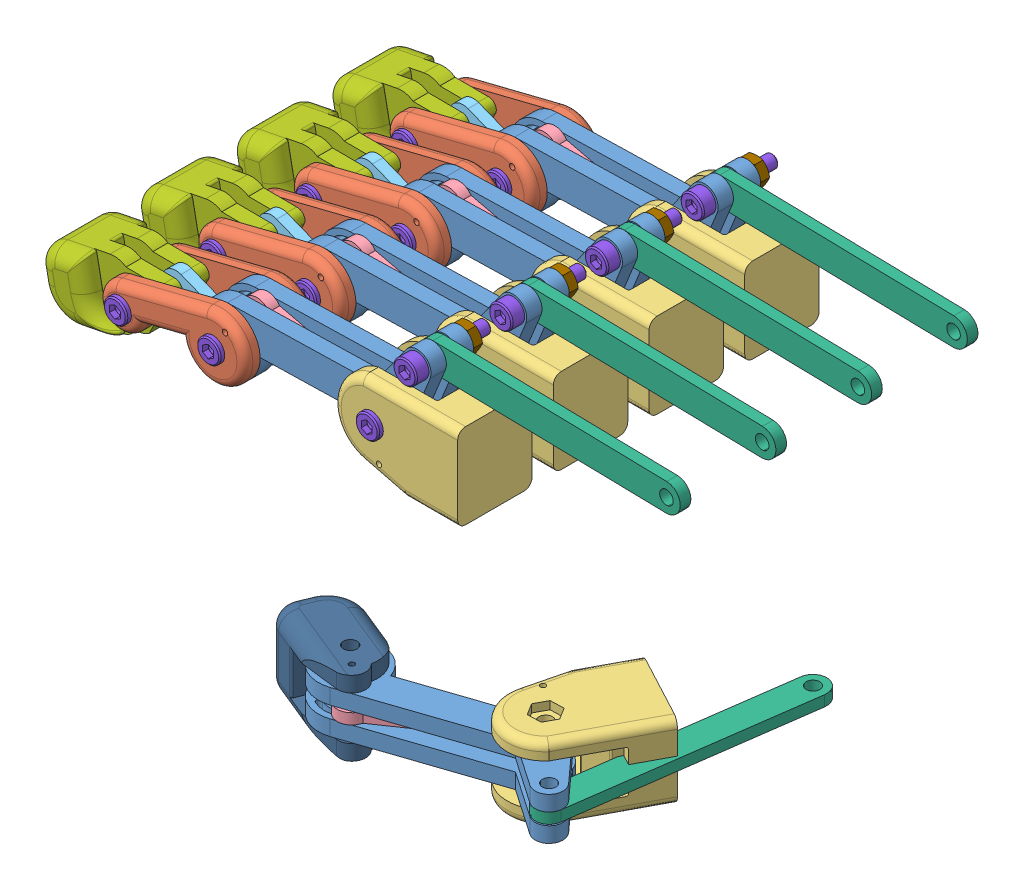
SolidWorks assembly Assem3, configuration Default. Lengths in mm.
Overall size (188.69 46.58 162.14).
79 component instances, 10 part files, 16 mates.
Components (placement in the parent):
- NotMyFinger-1: NotMyFinger [Default] at (20.0806 112.9124 103.3991) size (144.78 35.18 20.88) (flexible)
  - Joint1A-1: Joint1A [Default] at (46.4108 -14.225 49.7475) x (0.024106 -0.999709 0) z (0 0 -1) size (26.75 55.59 3.6)
  - Joint2A-1: Joint2A [HoleA] at (8.9819 -17.6283 53.3475) x (0.242286 -0.970205 0) z (0 0 -1) size (15 34.5 3.64)
  - Joint1A-2: Joint1A [Default] at (46.4108 -14.225 43.3475) x (0.024106 -0.999709 0) z (0 0 -1) size (26.75 55.59 3.6)
  - Joint2A-2: Joint2A [Default] at (8.9819 -17.6283 39.7475) x (0.242286 -0.970205 0) z (0 0 -1) size (15 34.5 3.64)
  - base-1: base [Default] at (66.6608 -5.475 35.9975) x (0 0 1) z (0 -1 0) size (17.57 29.25 20)
  - Link1A-1: Link1A [Default] at (48.1608 -21.475 43.3475) x (0.229287 0.973359 0) z (0.973359 -0.229287 0) size (10 2.5 45.77)
  - Link2A-1: Link2A [Default] at (9.1145 -23.1267 43.4475) x (0.370051 0.929011 0) z (0 0 1) size (6.5 24 2.5)
  - Link3A-1: Link3A [Default] at (108.4059 -1.7409 43.6475) x (0.999766 -0.021615 0) z (0 0 1) size (61.5 6.5 2.5)
  - FingerTip-1: FingerTip [Default] at (-12.9683 -20.5331 44.8225) x (-0.193934 0.981015 0) z (0 0 1) size (15.06 27.26 18.86)
  - socket head cap screw_am-1: socket head cap screw_am [B18.3.1M - 3 x 0.5 x 16 Hex SHCS -- 16NHX] at (-12.9683 -20.5331 54.4725) x (0 0 -1) z (1 0 0) size (19 5.5 5.5)
  - socket head cap screw_am-2: socket head cap screw_am [B18.3.1M - 3 x 0.5 x 16 Hex SHCS -- 16NHX] at (8.9819 -17.6283 54.4725) x (0 0 -1) z (1 0 0) size (19 5.5 5.5)
  - socket head cap screw_am-3: socket head cap screw_am [B18.3.1M - 3 x 0.5 x 16 Hex SHCS -- 16NHX] at (46.4108 -14.225 54.6225) x (0 0 -1) z (1 0 0) size (19 5.5 5.5)
  - hex nut style 1_am-1: hex nut style 1_am [B18.2.4.1M - Hex nut, Style 1,  M3 x 0.5 --D-N] at (46.4108 -14.225 35.4725) x (0.866025 0.5 0) z (0 0 -1) size (5.5 6.35 2.4)
  - hex nut style 1_am-2: hex nut style 1_am [B18.2.4.1M - Hex nut, Style 1,  M3 x 0.5 --D-N] at (8.9819 -17.6283 35.6225) x (0.719079 0.694929 0) z (0 0 -1) size (5.5 6.35 2.4)
  - hex nut style 1_am-3: hex nut style 1_am [B18.2.4.1M - Hex nut, Style 1,  M3 x 0.5 --D-N] at (-12.9683 -20.5331 35.6225) x (0.719079 0.694929 0) z (0 0 -1) size (5.5 6.35 2.4)
  - socket head cap screw_am-4: socket head cap screw_am [B18.3.1M - 3 x 0.5 x 16 Hex SHCS -- 16NHX] at (53.4188 -0.5521 52.7475) x (0 0 -1) z (1 0 0) size (19 5.5 5.5)
  - hex nut style 1_am-4: hex nut style 1_am [B18.2.4.1M - Hex nut, Style 1,  M3 x 0.5 --D-N] at (53.4188 -0.5521 37.3475) x (0.866025 0.5 0) z (0 0 -1) size (5.5 6.35 2.4)
- NotMyFinger-2: NotMyFinger [Default] at (20.0806 112.9124 80.8991) size (144.78 35.18 20.88) (flexible)
  - Joint1A-1: Joint1A [Default] at (46.4108 -14.225 49.7475) x (0.024106 -0.999709 0) z (0 0 -1) size (26.75 55.59 3.6)
  - Joint2A-1: Joint2A [HoleA] at (8.9819 -17.6283 53.3475) x (0.242286 -0.970205 0) z (0 0 -1) size (15 34.5 3.64)
  - Joint1A-2: Joint1A [Default] at (46.4108 -14.225 43.3475) x (0.024106 -0.999709 0) z (0 0 -1) size (26.75 55.59 3.6)
  - Joint2A-2: Joint2A [Default] at (8.9819 -17.6283 39.7475) x (0.242286 -0.970205 0) z (0 0 -1) size (15 34.5 3.64)
  - base-1: base [Default] at (66.6608 -5.475 35.9975) x (0 0 1) z (0 -1 0) size (17.57 29.25 20)
  - Link1A-1: Link1A [Default] at (48.1608 -21.475 43.3475) x (0.229287 0.973359 0) z (0.973359 -0.229287 0) size (10 2.5 45.77)
  - Link2A-1: Link2A [Default] at (9.1145 -23.1267 43.4475) x (0.370051 0.929011 0) z (0 0 1) size (6.5 24 2.5)
  - Link3A-1: Link3A [Default] at (108.4059 -1.7409 43.6475) x (0.999766 -0.021615 0) z (0 0 1) size (61.5 6.5 2.5)
  - FingerTip-1: FingerTip [Default] at (-12.9683 -20.5331 44.8225) x (-0.193934 0.981015 0) z (0 0 1) size (15.06 27.26 18.86)
  - socket head cap screw_am-1: socket head cap screw_am [B18.3.1M - 3 x 0.5 x 16 Hex SHCS -- 16NHX] at (-12.9683 -20.5331 54.4725) x (0 0 -1) z (1 0 0) size (19 5.5 5.5)
  - socket head cap screw_am-2: socket head cap screw_am [B18.3.1M - 3 x 0.5 x 16 Hex SHCS -- 16NHX] at (8.9819 -17.6283 54.4725) x (0 0 -1) z (1 0 0) size (19 5.5 5.5)
  - socket head cap screw_am-3: socket head cap screw_am [B18.3.1M - 3 x 0.5 x 16 Hex SHCS -- 16NHX] at (46.4108 -14.225 54.6225) x (0 0 -1) z (1 0 0) size (19 5.5 5.5)
  - hex nut style 1_am-1: hex nut style 1_am [B18.2.4.1M - Hex nut, Style 1,  M3 x 0.5 --D-N] at (46.4108 -14.225 35.4725) x (0.866025 0.5 0) z (0 0 -1) size (5.5 6.35 2.4)
  - hex nut style 1_am-2: hex nut style 1_am [B18.2.4.1M - Hex nut, Style 1,  M3 x 0.5 --D-N] at (8.9819 -17.6283 35.6225) x (0.719079 0.694929 0) z (0 0 -1) size (5.5 6.35 2.4)
  - hex nut style 1_am-3: hex nut style 1_am [B18.2.4.1M - Hex nut, Style 1,  M3 x 0.5 --D-N] at (-12.9683 -20.5331 35.6225) x (0.719079 0.694929 0) z (0 0 -1) size (5.5 6.35 2.4)
  - socket head cap screw_am-4: socket head cap screw_am [B18.3.1M - 3 x 0.5 x 16 Hex SHCS -- 16NHX] at (53.4188 -0.5521 52.7475) x (0 0 -1) z (1 0 0) size (19 5.5 5.5)
  - hex nut style 1_am-4: hex nut style 1_am [B18.2.4.1M - Hex nut, Style 1,  M3 x 0.5 --D-N] at (53.4188 -0.5521 37.3475) x (0.866025 0.5 0) z (0 0 -1) size (5.5 6.35 2.4)
- NotMyFinger-3: NotMyFinger [Default] at (20.0806 112.9124 58.3991) size (144.78 35.18 20.88) (flexible)
  - Joint1A-1: Joint1A [Default] at (46.4108 -14.225 49.7475) x (0.024106 -0.999709 0) z (0 0 -1) size (26.75 55.59 3.6)
  - Joint2A-1: Joint2A [HoleA] at (8.9819 -17.6283 53.3475) x (0.242286 -0.970205 0) z (0 0 -1) size (15 34.5 3.64)
  - Joint1A-2: Joint1A [Default] at (46.4108 -14.225 43.3475) x (0.024106 -0.999709 0) z (0 0 -1) size (26.75 55.59 3.6)
  - Joint2A-2: Joint2A [Default] at (8.9819 -17.6283 39.7475) x (0.242286 -0.970205 0) z (0 0 -1) size (15 34.5 3.64)
  - base-1: base [Default] at (66.6608 -5.475 35.9975) x (0 0 1) z (0 -1 0) size (17.57 29.25 20)
  - Link1A-1: Link1A [Default] at (48.1608 -21.475 43.3475) x (0.229287 0.973359 0) z (0.973359 -0.229287 0) size (10 2.5 45.77)
  - Link2A-1: Link2A [Default] at (9.1145 -23.1267 43.4475) x (0.370051 0.929011 0) z (0 0 1) size (6.5 24 2.5)
  - Link3A-1: Link3A [Default] at (108.4059 -1.7409 43.6475) x (0.999766 -0.021615 0) z (0 0 1) size (61.5 6.5 2.5)
  - FingerTip-1: FingerTip [Default] at (-12.9683 -20.5331 44.8225) x (-0.193934 0.981015 0) z (0 0 1) size (15.06 27.26 18.86)
  - socket head cap screw_am-1: socket head cap screw_am [B18.3.1M - 3 x 0.5 x 16 Hex SHCS -- 16NHX] at (-12.9683 -20.5331 54.4725) x (0 0 -1) z (1 0 0) size (19 5.5 5.5)
  - socket head cap screw_am-2: socket head cap screw_am [B18.3.1M - 3 x 0.5 x 16 Hex SHCS -- 16NHX] at (8.9819 -17.6283 54.4725) x (0 0 -1) z (1 0 0) size (19 5.5 5.5)
  - socket head cap screw_am-3: socket head cap screw_am [B18.3.1M - 3 x 0.5 x 16 Hex SHCS -- 16NHX] at (46.4108 -14.225 54.6225) x (0 0 -1) z (1 0 0) size (19 5.5 5.5)
  - hex nut style 1_am-1: hex nut style 1_am [B18.2.4.1M - Hex nut, Style 1,  M3 x 0.5 --D-N] at (46.4108 -14.225 35.4725) x (0.866025 0.5 0) z (0 0 -1) size (5.5 6.35 2.4)
  - hex nut style 1_am-2: hex nut style 1_am [B18.2.4.1M - Hex nut, Style 1,  M3 x 0.5 --D-N] at (8.9819 -17.6283 35.6225) x (0.719079 0.694929 0) z (0 0 -1) size (5.5 6.35 2.4)
  - hex nut style 1_am-3: hex nut style 1_am [B18.2.4.1M - Hex nut, Style 1,  M3 x 0.5 --D-N] at (-12.9683 -20.5331 35.6225) x (0.719079 0.694929 0) z (0 0 -1) size (5.5 6.35 2.4)
  - socket head cap screw_am-4: socket head cap screw_am [B18.3.1M - 3 x 0.5 x 16 Hex SHCS -- 16NHX] at (53.4188 -0.5521 52.7475) x (0 0 -1) z (1 0 0) size (19 5.5 5.5)
  - hex nut style 1_am-4: hex nut style 1_am [B18.2.4.1M - Hex nut, Style 1,  M3 x 0.5 --D-N] at (53.4188 -0.5521 37.3475) x (0.866025 0.5 0) z (0 0 -1) size (5.5 6.35 2.4)
- NotMyFinger-4: NotMyFinger [Default] at (20.0806 112.9124 35.8991) size (144.78 35.18 20.88) (flexible)
  - Joint1A-1: Joint1A [Default] at (46.4108 -14.225 49.7475) x (0.024106 -0.999709 0) z (0 0 -1) size (26.75 55.59 3.6)
  - Joint2A-1: Joint2A [HoleA] at (8.9819 -17.6283 53.3475) x (0.242286 -0.970205 0) z (0 0 -1) size (15 34.5 3.64)
  - Joint1A-2: Joint1A [Default] at (46.4108 -14.225 43.3475) x (0.024106 -0.999709 0) z (0 0 -1) size (26.75 55.59 3.6)
  - Joint2A-2: Joint2A [Default] at (8.9819 -17.6283 39.7475) x (0.242286 -0.970205 0) z (0 0 -1) size (15 34.5 3.64)
  - base-1: base [Default] at (66.6608 -5.475 35.9975) x (0 0 1) z (0 -1 0) size (17.57 29.25 20)
  - Link1A-1: Link1A [Default] at (48.1608 -21.475 43.3475) x (0.229287 0.973359 0) z (0.973359 -0.229287 0) size (10 2.5 45.77)
  - Link2A-1: Link2A [Default] at (9.1145 -23.1267 43.4475) x (0.370051 0.929011 0) z (0 0 1) size (6.5 24 2.5)
  - Link3A-1: Link3A [Default] at (108.4059 -1.7409 43.6475) x (0.999766 -0.021615 0) z (0 0 1) size (61.5 6.5 2.5)
  - FingerTip-1: FingerTip [Default] at (-12.9683 -20.5331 44.8225) x (-0.193934 0.981015 0) z (0 0 1) size (15.06 27.26 18.86)
  - socket head cap screw_am-1: socket head cap screw_am [B18.3.1M - 3 x 0.5 x 16 Hex SHCS -- 16NHX] at (-12.9683 -20.5331 54.4725) x (0 0 -1) z (1 0 0) size (19 5.5 5.5)
  - socket head cap screw_am-2: socket head cap screw_am [B18.3.1M - 3 x 0.5 x 16 Hex SHCS -- 16NHX] at (8.9819 -17.6283 54.4725) x (0 0 -1) z (1 0 0) size (19 5.5 5.5)
  - socket head cap screw_am-3: socket head cap screw_am [B18.3.1M - 3 x 0.5 x 16 Hex SHCS -- 16NHX] at (46.4108 -14.225 54.6225) x (0 0 -1) z (1 0 0) size (19 5.5 5.5)
  - hex nut style 1_am-1: hex nut style 1_am [B18.2.4.1M - Hex nut, Style 1,  M3 x 0.5 --D-N] at (46.4108 -14.225 35.4725) x (0.866025 0.5 0) z (0 0 -1) size (5.5 6.35 2.4)
  - hex nut style 1_am-2: hex nut style 1_am [B18.2.4.1M - Hex nut, Style 1,  M3 x 0.5 --D-N] at (8.9819 -17.6283 35.6225) x (0.719079 0.694929 0) z (0 0 -1) size (5.5 6.35 2.4)
  - hex nut style 1_am-3: hex nut style 1_am [B18.2.4.1M - Hex nut, Style 1,  M3 x 0.5 --D-N] at (-12.9683 -20.5331 35.6225) x (0.719079 0.694929 0) z (0 0 -1) size (5.5 6.35 2.4)
  - socket head cap screw_am-4: socket head cap screw_am [B18.3.1M - 3 x 0.5 x 16 Hex SHCS -- 16NHX] at (53.4188 -0.5521 52.7475) x (0 0 -1) z (1 0 0) size (19 5.5 5.5)
  - hex nut style 1_am-4: hex nut style 1_am [B18.2.4.1M - Hex nut, Style 1,  M3 x 0.5 --D-N] at (53.4188 -0.5521 37.3475) x (0.866025 0.5 0) z (0 0 -1) size (5.5 6.35 2.4)
- Thumb-1: Thumb [Default] at (185.4496 84.8281 177.4523) x (0 -1 0) z (-0.882383 0 -0.470531) size (17.69 96.11 65.16) (flexible)
  - base-1: base [Default] at (-2.6093 9.3209 33.628) size (17.57 29.25 20)
  - Joint1A-1: Joint1A [Default] at (4.7407 29.5709 42.378) x (0 -0.685985 0.727616) z (-1 0 0) size (26.75 55.59 3.6)
  - Joint1A-2: Joint1A [Default] at (11.1407 29.5709 42.378) x (0 -0.685985 0.727616) z (-1 0 0) size (26.75 55.59 3.6)
  - Link1A-1: Link1A [shorter] at (4.7407 27.8209 49.628) x (0 0.462623 -0.886555) z (0 -0.886555 -0.462623) size (10 2.5 40.77)
  - Link3A-1: Link3A [Default] at (4.7407 33.4942 27.5231) x (0 0.93868 -0.344789) z (1 0 0) size (61.5 6.5 2.5)
  - ThumbTip-1: ThumbTip [Default] at (5.9907 55.1415 69.9215) x (0 0.994953 -0.100344) z (1 0 0) size (15.03 25.92 17.5)
Mates (geometry in assembly coordinates):
- Coincident1: coincident aligned: plane of NotMyFinger-1/base-1 through (86.7413 87.4374 156.8966) normal (1 0 0); plane of NotMyFinger-2/base-1 through (86.7413 87.4374 134.3966) normal (1 0 0)
- Coincident2: coincident aligned: plane of NotMyFinger-2/base-1 through (86.7413 87.4374 134.3966) normal (1 0 0); plane of NotMyFinger-3/base-1 through (86.7413 87.4374 111.8966) normal (1 0 0)
- Coincident3: coincident aligned: plane of NotMyFinger-3/base-1 through (86.7413 87.4374 111.8966) normal (1 0 0); plane of NotMyFinger-4/base-1 through (86.7413 87.4374 89.3966) normal (1 0 0)
- Coincident4: coincident aligned: plane of NotMyFinger-1/base-1 through (86.7413 107.4374 139.3966) normal (0 1 0); plane of NotMyFinger-2/base-1 through (86.7413 107.4374 116.8966) normal (0 1 0)
- Coincident5: coincident aligned: plane of NotMyFinger-2/base-1 through (86.7413 107.4374 116.8966) normal (0 1 0); plane of NotMyFinger-3/base-1 through (86.7413 107.4374 94.3966) normal (0 1 0)
- Coincident6: coincident aligned: plane of NotMyFinger-3/base-1 through (86.7413 107.4374 94.3966) normal (0 1 0); plane of NotMyFinger-4/base-1 through (86.7413 107.4374 71.8966) normal (0 1 0)
- Coincident7: coincident anti-aligned: plane of NotMyFinger-1/base-1 through (86.7413 87.4374 139.3966) normal (0 -1 0); plane of Thumb-1/base-1 through (133.7433 87.4374 160.4432) normal (0 1 0)
- Distance1: distance = 5 mm anti-aligned: plane of NotMyFinger-1/base-1 through (86.7413 87.4374 139.3966) normal (0 0 -1); plane of NotMyFinger-2/base-1 through (56.7413 87.4374 134.3966) normal (0 0 1)
- Distance2: distance = 5 mm anti-aligned: plane of NotMyFinger-3/base-1 through (56.7413 87.4374 111.8966) normal (0 0 1); plane of NotMyFinger-2/base-1 through (86.7413 87.4374 116.8966) normal (0 0 -1)
- Distance4: distance = 5 mm anti-aligned: plane of NotMyFinger-3/base-1 through (86.7413 87.4374 94.3966) normal (0 0 -1); plane of NotMyFinger-4/base-1 through (56.7413 87.4374 89.3966) normal (0 0 1)
- Coincident16: coincident aligned: plane of NotMyFinger-3/Link3A-1 through (73.5696 115.6096 104.5466) normal (0.021615 0.999766 0); plane of NotMyFinger-4/Link3A-1 through (73.5696 115.6096 82.0466) normal (0.021615 0.999766 0)
- Coincident17: coincident aligned: plane of NotMyFinger-2/Link3A-1 through (73.5696 115.6096 127.0466) normal (0.021615 0.999766 0); plane of NotMyFinger-3/Link3A-1 through (73.5696 115.6096 104.5466) normal (0.021615 0.999766 0)
- Coincident18: coincident aligned: plane of NotMyFinger-1/Link3A-1 through (73.5696 115.6096 149.5466) normal (0.021615 0.999766 0); plane of NotMyFinger-2/Link3A-1 through (73.5696 115.6096 127.0466) normal (0.021615 0.999766 0)
- Concentric4: concentric aligned: cylinder of NotMyFinger-3/Link3A-1 through (128.4865 111.1715 104.5466) axis (0 0 -1) radius 1.6; cylinder of NotMyFinger-4/Link3A-1 through (128.4865 111.1715 82.0466) axis (0 0 -1) radius 1.6
- Concentric5: concentric aligned: cylinder of NotMyFinger-2/Link3A-1 through (128.4865 111.1715 127.0466) axis (0 0 -1) radius 1.6; cylinder of NotMyFinger-3/Link3A-1 through (128.4865 111.1715 104.5466) axis (0 0 -1) radius 1.6
- Concentric6: concentric aligned: cylinder of NotMyFinger-1/Link3A-1 through (128.4865 111.1715 149.5466) axis (0 0 -1) radius 1.6; cylinder of NotMyFinger-2/Link3A-1 through (128.4865 111.1715 127.0466) axis (0 0 -1) radius 1.6
